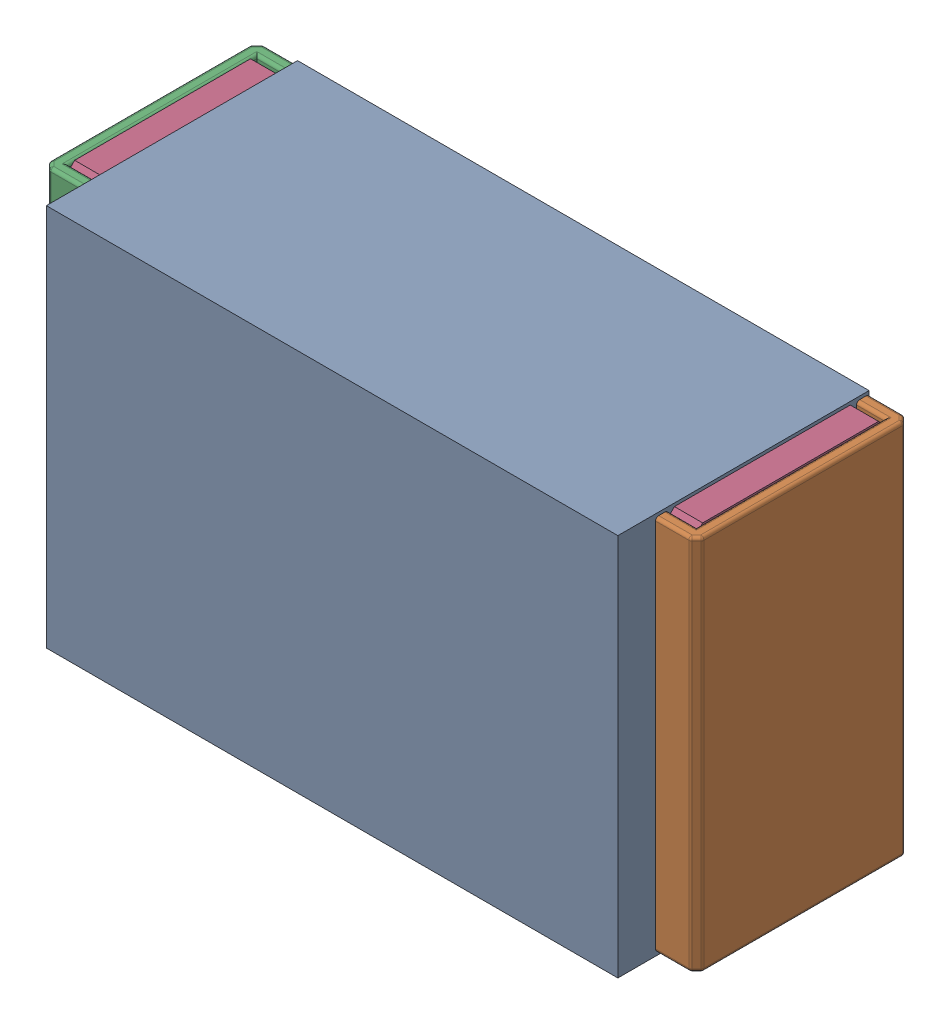
SolidWorks assembly R16, configuration Default. Lengths in mm.
Overall size (1.04 0.61 0.4).
3 component instances, 2 part files, 0 mates.
Components (placement in the parent):
- 1088880352-1: 1088880352 [Default] at (13.45 5.525 0) size (0.91 0.61 0.4)
  - Extruded-28-1: Extruded-28 [Default] at origin size (0.91 0.61 0.4)
- R0402-1: R0402 [Default] at (13.4501 5.5251 0) x (1 0 0) z (0 -1 0) size (1.04 0.34 0.6)
